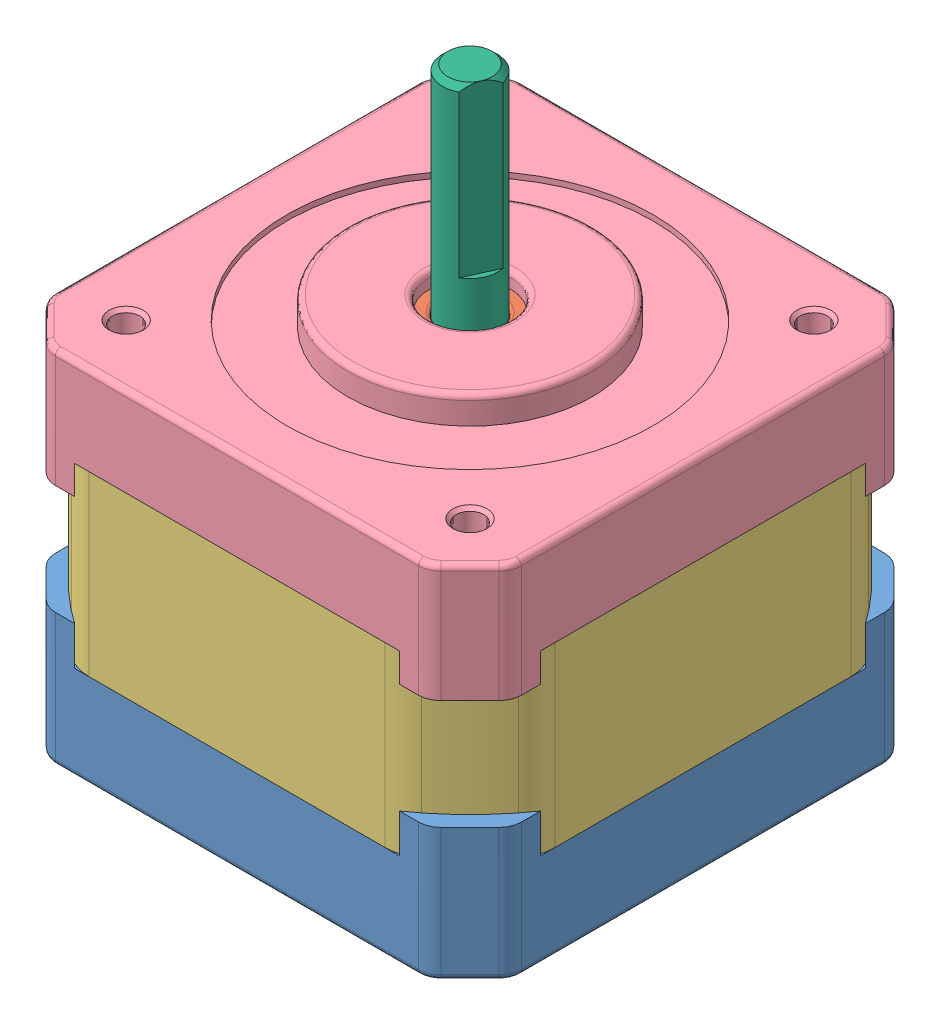
SolidWorks assembly 17HS13-0404S, configuration По умолчанию. Lengths in mm.
Overall size (42 52.5 42).
10 component instances, 6 part files, 16 mates.
Components (placement in the parent):
- nema17_bottom_33mm-1: nema17_bottom_33mm [По умолчанию] at origin size (42 12 42)
- radial ball bearing_68_din-1: radial ball bearing_68_din [DIN 625 - 625 - 8,SI,NC,8_68] at (0 5 0) x (0 -1 0) z (0 0 1) size (5 16 16)
- nema17_middle_33mm-1: nema17_middle_33mm [По умолчанию] at (0 8.5 0) size (42 16 42)
- nema17_top_33mm-1: nema17_top_33mm [По умолчанию] at (0 24.5 0) size (42 12.6 42)
- radial ball bearing_68_din-3: radial ball bearing_68_din [DIN 625 - 625 - 8,SI,NC,8_68] at (0 30.6 0) x (0 1 0) z (0 0 1) size (5 16 16)
- countersunk flat head cross recess screw_din-1: countersunk flat head cross recess screw_din [ISO 7046-1 - M3 x 25 - Z --- 25N] at (15.5 0.6 15.5) x (0 1 0) z (0.546944 0 -0.837169) size (25 5.5 5.5)
- countersunk flat head cross recess screw_din-2: countersunk flat head cross recess screw_din [ISO 7046-1 - M3 x 25 - Z --- 25N] at (15.5 0.6 -15.5) x (0 1 0) z (0.546944 0 -0.837169) size (25 5.5 5.5)
- countersunk flat head cross recess screw_din-3: countersunk flat head cross recess screw_din [ISO 7046-1 - M3 x 25 - Z --- 25N] at (-15.5 0.6 15.5) x (0 1 0) z (0.546944 0 -0.837169) size (25 5.5 5.5)
- countersunk flat head cross recess screw_din-4: countersunk flat head cross recess screw_din [ISO 7046-1 - M3 x 25 - Z --- 25N] at (-15.5 0.6 -15.5) x (0 1 0) z (0.546944 0 -0.837169) size (25 5.5 5.5)
- nema17_shaft_33mm-1: nema17_shaft_33mm [По умолчанию] at (0 1.5 0) x (-0.412738 0 0.91085) z (-0.91085 0 -0.412738) size (5 51 5)
Mates (geometry in assembly coordinates):
- Совпадение1: coincident: plane of nema17_bottom_33mm-1 through (0 2.5 0) normal (0 1 0); plane of radial ball bearing_68_din-1 through (7.7 2.5 0) normal (0 -1 0)
- Концентричный1: concentric: cylinder of nema17_bottom_33mm-1 through (0 2.5 0) axis (0 1 0) radius 8; cylinder of radial ball bearing_68_din-1 through (0 25.6375 0) axis (0 -1 0) radius 8
- Концентричный2: concentric: cylinder of nema17_bottom_33mm-1 through (15.5 8.5 15.5) axis (0 -1 0) radius 1.25; cylinder of nema17_middle_33mm-1 through (15.5 24.5 15.5) axis (0 -1 0) radius 1.25
- Концентричный3: concentric: cylinder of nema17_bottom_33mm-1 through (-15.5 8.5 -15.5) axis (0 -1 0) radius 1.25; cylinder of nema17_middle_33mm-1 through (-15.5 24.5 -15.5) axis (0 -1 0) radius 1.25
- Совпадение2: coincident: plane of nema17_bottom_33mm-1 through (0 8.5 0) normal (0 1 0); plane of nema17_middle_33mm-1 through (0 8.5 0) normal (0 -1 0)
- Концентричный4: concentric: cylinder of nema17_middle_33mm-1 through (15.5 24.5 15.5) axis (0 -1 0) radius 1.25; cylinder of nema17_top_33mm-1 through (15.5 32.5 15.5) axis (0 -1 0) radius 1.25
- Концентричный5: concentric: cylinder of nema17_middle_33mm-1 through (-15.5 24.5 -15.5) axis (0 -1 0) radius 1.25; cylinder of nema17_top_33mm-1 through (-15.5 32.5 -15.5) axis (0 -1 0) radius 1.25
- Совпадение3: coincident: plane of nema17_middle_33mm-1 through (0 24.5 0) normal (0 1 0); plane of nema17_top_33mm-1 through (0 24.5 0) normal (0 -1 0)
- Совпадение4: coincident: plane of nema17_top_33mm-1 through (0 33.1 0) normal (0 -1 0); plane of radial ball bearing_68_din-3 through (-7.7 33.1 0) normal (0 1 0)
- Концентричный6: concentric: cylinder of nema17_top_33mm-1 through (0 33.1 0) axis (0 -1 0) radius 8; cylinder of radial ball bearing_68_din-3 through (0 9.9625 0) axis (0 1 0) radius 8
- Совпадение5: coincident: cone of nema17_bottom_33mm-1 through (15.5 0 15.5) axis (0 1 0); cone of countersunk flat head cross recess screw_din-1 through (15.5 1 15.5) axis (0 1 0)
- Совпадение6: coincident: cone of nema17_bottom_33mm-1 through (15.5 0 -15.5) axis (0 1 0); cone of countersunk flat head cross recess screw_din-2 through (15.5 1 -15.5) axis (0 1 0)
- Совпадение7: coincident: cone of nema17_bottom_33mm-1 through (-15.5 0 15.5) axis (0 1 0); cone of countersunk flat head cross recess screw_din-3 through (-15.5 1 15.5) axis (0 1 0)
- Совпадение8: coincident: cone of nema17_bottom_33mm-1 through (-15.5 0 -15.5) axis (0 1 0); cone of countersunk flat head cross recess screw_din-4 through (-15.5 1 -15.5) axis (0 1 0)
- Концентричный8: concentric: cylinder of nema17_top_33mm-1 through (0 34.5 0) axis (0 -1 0) radius 3.65; cylinder of nema17_shaft_33mm-1 through (0 52.5 0) axis (0 -1 0) radius 2.5
- Расстояние1: distance = 20 mm: plane of nema17_shaft_33mm-1 through (0 52.5 0) normal (0 1 0); plane of nema17_top_33mm-1 through (0 32.5 0) normal (0 1 0)
